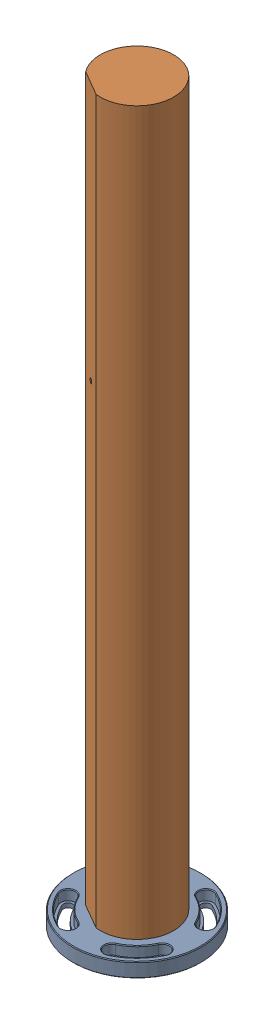
SolidWorks assembly assemZeissHolderPillar, configuration Default. Lengths in mm.
Overall size (88.9 510 88.9).
2 component instances, 2 part files, 3 mates.
Components (placement in the parent):
- baseRoundPlate-2: baseRoundPlate [Default] at (-12.8181 -7.6108 11.9346) x (0 0 -1) z (-1 0 0) size (88.9 10 88.9)
- d_shaft-v3-1: d_shaft-v3 [Default] at (-12.8181 -7.6108 11.9346) x (0.866025 0 0.5) z (-0.5 0 0.866025) size (50.8 500.02 48.75)
Mates (geometry in assembly coordinates):
- Coincident1: coincident anti-aligned: plane of baseRoundPlate-2 through (-12.8181 -7.6108 11.9346) normal (0 1 0); plane of d_shaft-v3-1 through (-12.8181 -7.6108 11.9346) normal (0 -1 0)
- Concentric1: concentric aligned: circle of baseRoundPlate-2; circle of d_shaft-v3-1
- Concentric2: concentric aligned: cylinder of baseRoundPlate-2 through (-20.1505 -7.6108 -0.7654) axis (0 -1 0) radius 5; circle of d_shaft-v3-1
